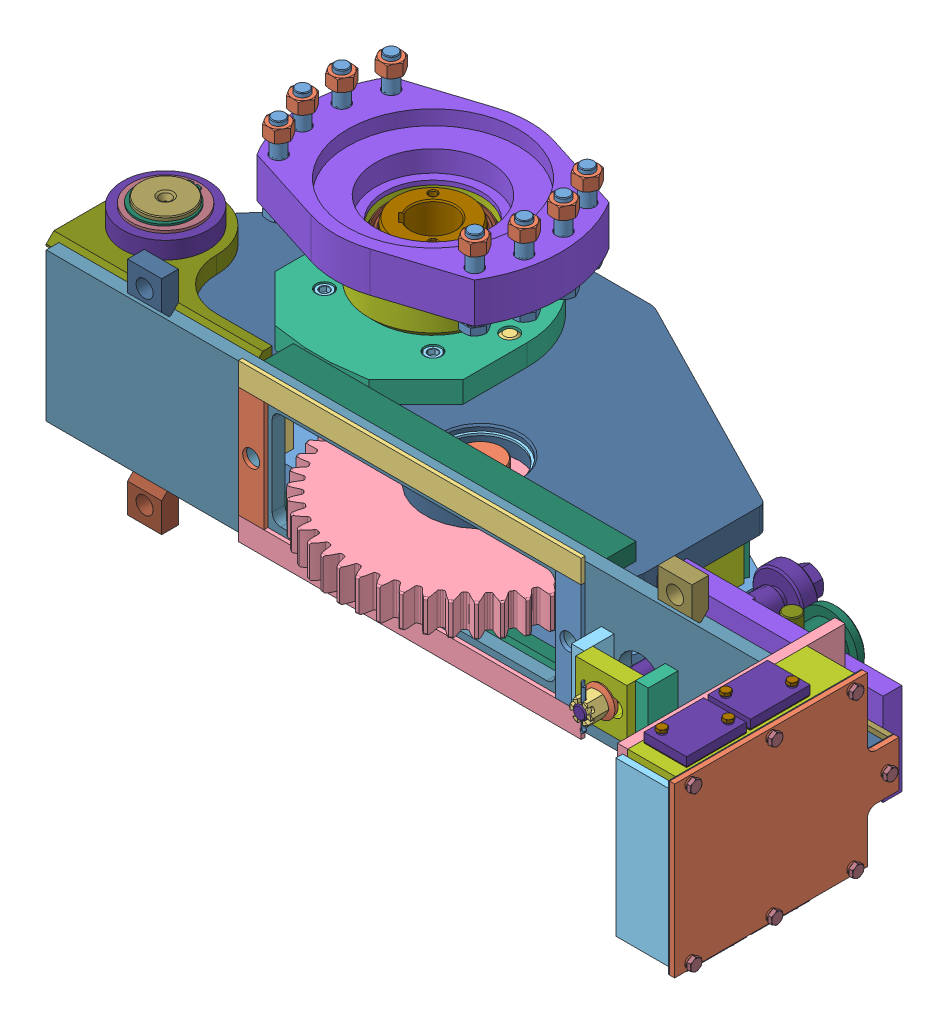
SolidWorks assembly g1_3_1_1, configuration 默认. Lengths in mm.
Overall size (957.4 359.9 530).
207 component instances, 96 part files, 0 mates.
Components (placement in the parent):
- g1_3_1_1_5_2-1: g1_3_1_1_5_2 [默认] at origin size (926 108 318.6)
  - g1_3_1_1_5-1_af1_2-1: g1_3_1_1_5-1_af1_2 [默认] at origin size (661 29 318.6)
  - g1_3_1_1_5-2_af0_2-1: g1_3_1_1_5-2_af0_2 [默认] at (-213.2 29 0) size (100 50 100)
  - g1_3_1_1_5-3_2-1: g1_3_1_1_5-3_2 [默认] at (-103.2 54 50) x (1 0 0) z (0 1 0) size (160 10 50)
  - g1_3_1_1_5-4_2-1: g1_3_1_1_5-4_2 [默认] at (-149.9151 54 -132.7301) x (0 1 0) z (-0.659692 0 0.751536) size (50 10 223)
  - g1_3_1_1_5-5_2-1: g1_3_1_1_5-5_2 [默认] at (20.5 54 -217) x (1 0 0) z (0 1 0) size (194 10 50)
  - g1_3_1_1_5-6_2-1: g1_3_1_1_5-6_2 [默认] at (248.4498 54 -161.5242) x (0 1 0) z (0.890083 0 0.455798) size (50 10 284)
  - g1_3_1_1_5-7_2-1: g1_3_1_1_5-7_2 [默认] at (377.8 54 -43.9) x (0 0 -1) z (0 1 0) size (87 10 50)
  - g1_3_1_1_5-9_af0_2-1: g1_3_1_1_5-9_af0_2 [默认] at (502.8 54 24.6) x (1 0 0) z (0 1 0) size (300 25 108)
  - g1_3_1_1_5-8_2-1: g1_3_1_1_5-8_2 [默认] at (437.8 54 49.6) x (1 0 0) z (0 1 0) size (60 50 60)
  - g1_3_1_1_5-1_af0_2-1: g1_3_1_1_5-1_af0_2 [默认] at (0 79 0) size (661 29 318.6)
  - g1_3_1_1_5_more_2-1: g1_3_1_1_5_more_2 [默认] at origin size (139.2 108 206.2)
- g1_3_1_1_4_2-1: g1_3_1_1_4_2 [默认] at (-213.2 -63.3 0) size (80 236.35 80)
  - g1_3_1_1_4-1_2-1: g1_3_1_1_4-1_2 [默认] at origin size (60 234 60.04)
  - g1_3_1_1_4-3_2-1: g1_3_1_1_4-3_2 [默认] at (0 6.7 0) size (80 3 80)
  - g1_3_1_1_4-3_2-2: g1_3_1_1_4-3_2 [默认] at (0 224.3 0) size (80 3 80)
  - g1_3_1_1_4-2_2-1: g1_3_1_1_4-2_2 [默认] at (0 174.3 0) size (72 50 72)
  - g1_3_1_1_4-2_2-2: g1_3_1_1_4-2_2 [默认] at (0 9.7 0) size (72 50 72)
  - g1_3_1_1_4-2_2-3: g1_3_1_1_4-2_2 [默认] at (0 62.7 0) size (72 50 72)
  - g1_3_1_1_4-2_2-4: g1_3_1_1_4-2_2 [默认] at (0 121.3 0) size (72 50 72)
  - 60_gb894_1_2-1: 60_gb894_1_2 [默认] at (1.95 4.5 -28.4332) x (-1 0 0) z (0 1 0) size (65.16 69.76 2)
  - 60_gb894_1_2-2: 60_gb894_1_2 [默认] at (1.95 227.5 -28.4332) x (-1 0 0) z (0 1 0) size (65.16 69.76 2)
  - 10_jb982_2-1: 10_jb982_2 [默认] at (0 -1 0) size (16 2.7 16)
- g1_3_1_1_2_2-1: g1_3_1_1_2_2 [默认] at (0 -30 -100.4) size (219.6 152 245)
  - g1_3_1_1_2-1_2-1: g1_3_1_1_2-1_2 [默认] at origin size (219.6 61 245)
  - g1_3_1_1_2-2_2-1: g1_3_1_1_2-2_2 [默认] at (0 152 0) x (-0.047609 0 0.998866) z (0 1 0) size (120.16 120.16 117)
  - g1_3_1_1_2-3_2-1: g1_3_1_1_2-3_2 [默认] at (-20.1525 129 20.1525) x (0 -1 0) z (0.707107 0 0.707107) size (28 11 14)
- g1_3_1_1_3_2-1: g1_3_1_1_3_2 [默认] at (172.8 54 16.6) x (0 -1 0) z (0 0 1) size (103.5 321.87 322.01)
  - g1_3_1_1_3-1_2-1: g1_3_1_1_3-1_2 [默认] at origin size (103.5 52 52)
  - 16x10x45_gb1096_2-1: 16x10x45_gb1096_2 [默认] at (-0.5 0 25) x (1 0 0) z (0 0 -1) size (45 16 10)
  - _X2_60F08F6E_X0_g1_3_1_1_3-2_2-1: _X2_60F08F6E_X0_g1_3_1_1_3-2_2 [默认] at (25 0 0) x (0 0 1) z (1 0 0) size (322.01 321.87 50.08)
  - 90_gb893_1_2-1: 90_gb893_1_2 [默认] at (45.05 0 -2.4333) x (0 1 0) z (1 0 0) size (93.5 89.63 2.5)
  - 90_gb893_1_2-2: 90_gb893_1_2 [默认] at (-47.55 0 -2.4333) x (0 1 0) z (1 0 0) size (93.5 89.63 2.5)
- g1_3_1_1_1_3-1: g1_3_1_1_1_3 [默认] at (0 83 -100.4) size (300 165.8 249)
  - g1_3_1_1_1_1_2-1: g1_3_1_1_1_1_2 [默认] at origin size (300 154 249)
    - g1_3_1_1_1_1-1_af0_2-1: g1_3_1_1_1_1-1_af0_2 [默认] at origin size (220 42 245)
    - g1_3_1_1_1_1-2_af0_2-1: g1_3_1_1_1_1-2_af0_2 [默认] at (0 50 0) size (150 65.01 150)
    - g1_3_1_1_1_1-3_af0_2-1: g1_3_1_1_1_1-3_af0_2 [默认] at (0 140 0) size (300 47 228)
  - g1_3_1_1_1-2_2-1: g1_3_1_1_1-2_2 [默认] at (0 122.2 0) x (0.707107 0 0.707107) z (0.707107 0 -0.707107) size (90 126 90)
  - g1_3_1_1_1-1_2-1: g1_3_1_1_1-1_2 [默认] at (0 77 0) x (0 1 0) z (0 0 1) size (20 110 110)
  - b90x110x12_gb9877_1_2-1: b90x110x12_gb9877_1_2 [默认] at (0 66.9 0) size (108.6 17.9 108.6)
    - b90x110x12_gb9877_1_rubber_2-1: b90x110x12_gb9877_1_rubber_2 [默认] at origin size (108.6 12 108.6)
    - b90x110x12_gb9877_1_frame_2-1: b90x110x12_gb9877_1_frame_2 [默认] at (0 -2.4 0) x (-1 0 0) z (0 0 1) size (107.2 9.5 107.2)
  - b90x110x12_gb9877_1_2-2: b90x110x12_gb9877_1_2 [默认] at (0 104.8 0) size (108.6 17.9 108.6)
    - b90x110x12_gb9877_1_rubber_2-1: b90x110x12_gb9877_1_rubber_2 [默认] at origin size (108.6 12 108.6)
    - b90x110x12_gb9877_1_frame_2-1: b90x110x12_gb9877_1_frame_2 [默认] at (0 -2.4 0) x (-1 0 0) z (0 0 1) size (107.2 9.5 107.2)
  - 80_gb894_1_2-1: 80_gb894_1_2 [默认] at (-2.4 11.1 -38.1746) x (1 0 0) z (0 -1 0) size (85.83 90.87 2.5)
- g1_3_1_1_6_2-1: g1_3_1_1_6_2 [默认] at (172.8 54 95) x (1 0 0) z (0 1 0) size (880 200 260)
  - g1_3_1_1_6-4_af0_2-1: g1_3_1_1_6-4_af0_2 [默认] at origin size (850 15 174)
  - g1_3_1_1_6-8_2-1: g1_3_1_1_6-8_2 [默认] at (0 40 57) x (1 0 0) z (0 -1 0) size (402 20 44.8)
  - g1_3_1_1_6-8_2-2: g1_3_1_1_6-8_2 [默认] at (0 40 -77) x (1 0 0) z (0 -1 0) size (402 20 44.8)
  - g1_3_1_1_6-1_2-1: g1_3_1_1_6-1_2 [默认] at (-386 95 -87) x (1 0 0) z (0 -1 0) size (245 20 140)
  - g1_3_1_1_6-1_2-2: g1_3_1_1_6-1_2 [默认] at (-386 95 67) x (1 0 0) z (0 -1 0) size (245 20 140)
  - g1_3_1_1_6-3_2-1: g1_3_1_1_6-3_2 [默认] at (-386 95 87) x (-1 0 0) z (0 1 0) size (100 20 100)
  - g1_3_1_1_6-3_2-2: g1_3_1_1_6-3_2 [默认] at (-386 95 -107) x (-1 0 0) z (0 1 0) size (100 20 100)
  - g1_3_1_1_6-2_2-1: g1_3_1_1_6-2_2 [默认] at (-386 95 57) x (-1 0 0) z (0 1 0) size (100 10 100)
  - g1_3_1_1_6-2_2-2: g1_3_1_1_6-2_2 [默认] at (-386 95 -57) x (1 0 0) z (0 1 0) size (100 10 100)
  - g1_3_1_1_6-6_af1_2-1: g1_3_1_1_6-6_af1_2 [默认] at (186 -5 0) x (0 0 -1) z (1 0 0) size (130 4.6 30)
  - g1_3_1_1_6-6_af0_2-1: g1_3_1_1_6-6_af0_2 [默认] at (-186 -5 0) x (0 0 -1) z (1 0 0) size (130 4.6 30)
  - g1_3_1_1_6-7_af0_2-1: g1_3_1_1_6-7_af0_2 [默认] at (0 0 78.5) x (1 0 0) z (0 0 -1) size (402 4.6 27)
  - g1_3_1_1_6-7_af1_2-1: g1_3_1_1_6-7_af1_2 [默认] at (0 -5 -78.5) size (402 4.6 27)
  - g1_3_1_1_6-9_2-1: g1_3_1_1_6-9_2 [默认] at (220 -17 0) x (0 1 0) z (0 0 -1) size (35 15 60)
  - g1_3_1_1_6-9_af0_2-1: g1_3_1_1_6-9_af0_2 [默认] at (310 -17 0) x (0 1 0) z (0 0 1) size (35 15 60)
  - g1_3_1_1_6-10_2-1: g1_3_1_1_6-10_2 [默认] at (265 -45 0) size (60 20 60)
  - g1_3_1_1_6-12_af0_2-1: g1_3_1_1_6-12_af0_2 [默认] at (434 25 0.5) x (0 0 1) z (0 -1 0) size (120 25 80)
  - g1_3_1_1_6-11_af0_2-1: g1_3_1_1_6-11_af0_2 [默认] at (357 15 0) size (94 40 60)
  - g1_3_1_1_6-5_af0_2-1: g1_3_1_1_6-5_af0_2 [默认] at (-311 -5 108.5) x (0 0 -1) z (1 0 0) size (43 19.6 40)
  - g1_3_1_1_6-5_af1_2-1: g1_3_1_1_6-5_af1_2 [默认] at (-311 -5 -108.5) x (0 0 1) z (-1 0 0) size (43 19.6 40)
  - g1_3_1_1_6-5_af2_2-1: g1_3_1_1_6-5_af2_2 [默认] at (311 -5 108.5) x (0 0 -1) z (1 0 0) size (43 19.6 40)
  - g1_3_1_1_6-5_af3_2-1: g1_3_1_1_6-5_af3_2 [默认] at (311 -5 -108.5) x (0 0 1) z (-1 0 0) size (43 19.6 40)
  - g1_3_1_1_6_more_2-1: g1_3_1_1_6_more_2 [默认] at origin size (109 70.2 96)
- g1_3_1_1-1_2-1: g1_3_1_1-1_2 [默认] at (512.8 54 49.5) x (1 0 0) z (0 1 0) size (70 135 70)
- g1_3_1_1-2_2-1: g1_3_1_1-2_2 [默认] at (512.8 43 -8.5) x (0 1 0) z (0 0 1) size (130 25 25)
- g1_3_1_1_7_2-1: g1_3_1_1_7_2 [默认] at (437.8 54 78.9833) x (0 0 1) z (0 1 0) size (272.02 63.51 60)
  - g1_3_1_1_7-1_2-1: g1_3_1_1_7-1_2 [默认] at origin size (272.02 60 60)
  - g1_3_1_1_7-2_2-1: g1_3_1_1_7-2_2 [默认] at (-104.3833 -31.7543 0) x (0 1 0) z (1 0 0) size (63.51 55 25)
  - 4x40_gb91_2-1: 4x40_gb91_2 [默认] at (82.0173 -2 29.7543) x (0 0 1) z (-1 -0.000312 0) size (52 6.04 4)
  - a35_5_gb1972_2-1: a35_5_gb1972_2 [默认] at (39.2167 0 0) x (0 0.075145 0.997173) z (0 0.997173 -0.075145) size (35.5 7.2 35.5)
  - a35_5_gb1972_2-2: a35_5_gb1972_2 [默认] at (62.8167 0 0) x (0 -0.99777 0.066751) z (0 -0.066751 -0.99777) size (35.5 7.2 35.5)
  - m16a_gb6178_2-1: m16a_gb6178_2 [默认] at (85.8167 13.8564 0) x (0 -1 0) z (-1 0 0) size (27.71 24 20.8)
- g1_3_1_1_8_2-1: g1_3_1_1_8_2 [默认] at (601.8 66.5 157.5) x (0 -1 0) z (0 0 1) size (230.2 85.4 268.3)
  - g1_3_1_1_8_1_af0_2-1: g1_3_1_1_8_1_af0_2 [默认] at origin size (197 68 263)
    - g1_3_1_1_8_1-3_af1_2-1: g1_3_1_1_8_1-3_af1_2 [默认] at origin size (197 12 255)
    - g1_3_1_1_8_1-1_2-1: g1_3_1_1_8_1-1_2 [默认] at (0 37 127.5) x (1 0 0) z (0 -1 0) size (181 8 62)
    - g1_3_1_1_8_1-2_af1_2-1: g1_3_1_1_8_1-2_af1_2 [默认] at (98.5 40 22.5) x (0 1 0) z (0 0 1) size (56 16 210)
    - g1_3_1_1_8_1-2_af0_2-1: g1_3_1_1_8_1-2_af0_2 [默认] at (-98.5 40 22.5) x (0 1 0) z (0 0 -1) size (56 16 210)
    - g1_3_1_1_8_1-5_2-1: g1_3_1_1_8_1-5_2 [默认] at (0 40 -82.5) x (1 0 0) z (0 1 0) size (165 8 56)
    - g1_3_1_1_8_1-7_af0_2-1: g1_3_1_1_8_1-7_af0_2 [默认] at (12.5 57 -106) size (30 6 31)
    - g1_3_1_1_8_1-6_2-1: g1_3_1_1_8_1-6_2 [默认] at (27.5 40 -106) x (0 1 0) z (0 0 -1) size (56 6 31)
    - g1_3_1_1_8_1-6_2-2: g1_3_1_1_8_1-6_2 [默认] at (-8.5 40 -106) x (0 1 0) z (0 0 -1) size (56 6 31)
    - g1_3_1_1_8_1-4_af1_2-1: g1_3_1_1_8_1-4_af1_2 [默认] at (-10 12 5) size (105 17 85)
    - g1_3_1_1_8_1-8_af0_2-1: g1_3_1_1_8_1-8_af0_2 [默认] at (12.5 40 -127.5) x (0 1 0) z (1 0 0) size (56 6 54)
    - g1_3_1_1_8_1_af0_more_2-1: g1_3_1_1_8_1_af0_more_2 [默认] at origin size (197 61 238)
  - g1_3_1_1_8-3_2-1: g1_3_1_1_8-3_2 [默认] at (12.5 37 -32.7987) x (0 0 -1) z (0 1 0) size (229 15 15)
  - g1_3_1_1_8-6_2-1: g1_3_1_1_8-6_2 [默认] at (12.5 37 30.1) x (-1 0 0) z (0 1 0) size (26 60 26)
  - g1_3_1_1_8-5_2-1: g1_3_1_1_8-5_2 [默认] at (12.5 29 -27.5) size (60 24 20)
  - g1_3_1_1_8-1_2-1: g1_3_1_1_8-1_2 [默认] at (109.5 39.7 76.2) x (0 0 -1) z (0 1 0) size (70 10 50)
  - g1_3_1_1_8-1_2-2: g1_3_1_1_8-1_2 [默认] at (109.5 39.7 1.2) x (0 0 -1) z (0 1 0) size (70 10 50)
  - g1_3_1_1_8-1_2-3: g1_3_1_1_8-1_2 [默认] at (-99.5 40.3 76.8) x (0 0 1) z (0 -1 0) size (70 10 50)
  - g1_3_1_1_8-1_2-4: g1_3_1_1_8-1_2 [默认] at (-99.5 39.7 1.2) x (0 0 -1) z (0 1 0) size (70 10 50)
  - g1_3_1_1_8-2_2-1: g1_3_1_1_8-2_2 [默认] at (99.5 39.7 76.8) x (0 1 0) z (0 0 1) size (50 1 70)
  - g1_3_1_1_8-2_2-2: g1_3_1_1_8-2_2 [默认] at (99.5 39.7 1.8) x (0 1 0) z (0 0 1) size (50 1 70)
  - g1_3_1_1_8-2_2-3: g1_3_1_1_8-2_2 [默认] at (-98.5 40.3 76.8) x (0 1 0) z (0 0 1) size (50 1 70)
  - g1_3_1_1_8-2_2-4: g1_3_1_1_8-2_2 [默认] at (-98.5 39.7 1.8) x (0 1 0) z (0 0 1) size (50 1 70)
  - g1_3_1_1_8-8_2-1: g1_3_1_1_8-8_2 [默认] at (0 68 22.5) x (0 0 -1) z (1 0 0) size (263 1 197)
  - g1_3_1_1_8-7_2-1: g1_3_1_1_8-7_2 [默认] at (0 69 22.5) x (0 0 -1) z (1 0 0) size (263 6 197)
  - g1_3_1_1_8-9_af0_2-1: g1_3_1_1_8-9_af0_2 [默认] at (-42.5 17 5.5) size (34 10 74)
  - g1_3_1_1_8-10_2-1: g1_3_1_1_8-10_2 [默认] at (12.5 37 -127.5) x (1 0 0) z (0 1 0) size (40 2 32)
  - g1_3_1_1_8-4_2-1: g1_3_1_1_8-4_2 [默认] at (12.5 37 -69.8) x (1 0 0) z (0 1 0) size (22 3 22)
  - ya2x20x90-2_gb2089_af0_2-1: ya2x20x90-2_gb2089_af0_2 [默认] at (12.5 37 -82.5) x (0 0 -1) z (1 0 0) size (92.3 24.62 24.71)
  - 14x2_65_gb3452_1_2-1: 14x2_65_gb3452_1_2 [默认] at (12.5 37 -124.5) x (0 0 1) z (0 1 0) size (2.65 19.38 19.38)
  - 6_gb93_2-1: 6_gb93_2 [默认] at (111.1 54.3 -23.2) x (0 -1 0) z (-1 0 0) size (9.3 9.3 1.6)
  - m6x20_gb5783_2-1: m6x20_gb5783_2 [默认] at (111.1 54.3 -23.2) x (0 -1 0) z (0 0 1) size (11.55 24 10)
  - 6_gb93_2-2: 6_gb93_2 [默认] at (111.1 25.7 26.2) x (0 -1 0) z (-1 0 0) size (9.3 9.3 1.6)
  - m6x20_gb5783_2-2: m6x20_gb5783_2 [默认] at (111.1 25.7 26.2) x (0 -1 0) z (0 0 1) size (11.55 24 10)
  - 6_gb93_2-3: 6_gb93_2 [默认] at (111.1 54.3 51.8) x (0 -1 0) z (-1 0 0) size (9.3 9.3 1.6)
  - m6x20_gb5783_2-3: m6x20_gb5783_2 [默认] at (111.1 54.3 51.8) x (0 -1 0) z (0 0 1) size (11.55 24 10)
  - 6_gb93_2-4: 6_gb93_2 [默认] at (111.1 25.7 101.2) x (0 -1 0) z (-1 0 0) size (9.3 9.3 1.6)
  - m6x20_gb5783_2-4: m6x20_gb5783_2 [默认] at (111.1 25.7 101.2) x (0 -1 0) z (0 0 1) size (11.55 24 10)
  - 6_gb93_2-5: 6_gb93_2 [默认] at (-111.1 54.3 -23.2) x (0 1 0) z (1 0 0) size (9.3 9.3 1.6)
  - m6x20_gb5783_2-5: m6x20_gb5783_2 [默认] at (-111.1 54.3 -23.2) x (0 1 0) z (0 0 1) size (11.55 24 10)
  - 6_gb93_2-6: 6_gb93_2 [默认] at (-111.1 25.7 26.2) x (0 1 0) z (1 0 0) size (9.3 9.3 1.6)
  - m6x20_gb5783_2-6: m6x20_gb5783_2 [默认] at (-111.1 25.7 26.2) x (0 1 0) z (0 0 1) size (11.55 24 10)
  - 6_gb93_2-7: 6_gb93_2 [默认] at (-111.1 54.3 51.8) x (0 1 0) z (1 0 0) size (9.3 9.3 1.6)
  - m6x20_gb5783_2-7: m6x20_gb5783_2 [默认] at (-111.1 54.3 51.8) x (0 1 0) z (0 0 1) size (11.55 24 10)
  - 6_gb93_2-8: 6_gb93_2 [默认] at (-111.1 25.7 101.2) x (0 1 0) z (1 0 0) size (9.3 9.3 1.6)
  - m6x20_gb5783_2-8: m6x20_gb5783_2 [默认] at (-111.1 25.7 101.2) x (0 1 0) z (0 0 1) size (11.55 24 10)
  - 15_gb894_1_2-1: 15_gb894_1_2 [默认] at (12 29.8675 -73.9) size (17.18 18.67 1.11)
  - 15_gb894_1_2-2: 15_gb894_1_2 [默认] at (12 29.8675 29) size (17.18 18.67 1.11)
  - 15_gb894_1_2-3: 15_gb894_1_2 [默认] at (12 29.8675 134.5) size (17.18 18.67 1.11)
  - 8_gb93_2-1: 8_gb93_2 [默认] at (32.5 53 -27.5) x (-1 0 0) z (0 1 0) size (12.3 12.3 2.1)
  - m8x40_gb5782_2-1: m8x40_gb5782_2 [默认] at (32.5 55.1 -27.5) size (15.01 45.3 13)
  - 8_gb93_2-2: 8_gb93_2 [默认] at (-7.5 53 -27.5) x (-1 0 0) z (0 1 0) size (12.3 12.3 2.1)
  - m8x40_gb5782_2-2: m8x40_gb5782_2 [默认] at (-7.5 55.1 -27.5) size (15.01 45.3 13)
  - 8_gb93_2-3: 8_gb93_2 [默认] at (90.5 75 -72.5) x (-1 0 0) z (0 1 0) size (12.3 12.3 2.1)
  - m8x20_gb5783_dakexiu_2-1: m8x20_gb5783_dakexiu_2 [默认] at (90.5 77.1 -72.5) size (15.01 25.3 13)
  - 8_gb93_2-4: 8_gb93_2 [默认] at (90.5 75 22.5) x (-1 0 0) z (0 1 0) size (12.3 12.3 2.1)
  - m8x20_gb5783_dakexiu_2-2: m8x20_gb5783_dakexiu_2 [默认] at (90.5 77.1 22.5) size (15.01 25.3 13)
  - 8_gb93_2-5: 8_gb93_2 [默认] at (90.5 75 117.5) x (-1 0 0) z (0 1 0) size (12.3 12.3 2.1)
  - m8x20_gb5783_dakexiu_2-3: m8x20_gb5783_dakexiu_2 [默认] at (90.5 77.1 117.5) size (15.01 25.3 13)
  - 8_gb93_2-6: 8_gb93_2 [默认] at (-90.5 75 117.5) x (-1 0 0) z (0 1 0) size (12.3 12.3 2.1)
  - m8x20_gb5783_dakexiu_2-4: m8x20_gb5783_dakexiu_2 [默认] at (-90.5 77.1 117.5) size (15.01 25.3 13)
  - 8_gb93_2-7: 8_gb93_2 [默认] at (-90.5 75 22.5) x (-1 0 0) z (0 1 0) size (12.3 12.3 2.1)
  - m8x20_gb5783_dakexiu_2-5: m8x20_gb5783_dakexiu_2 [默认] at (-90.5 77.1 22.5) size (15.01 25.3 13)
  - 8_gb93_2-8: 8_gb93_2 [默认] at (-90.5 75 -72.5) x (-1 0 0) z (0 1 0) size (12.3 12.3 2.1)
  - m8x20_gb5783_dakexiu_2-6: m8x20_gb5783_dakexiu_2 [默认] at (-90.5 77.1 -72.5) size (15.01 25.3 13)
  - 8_gb93_2-9: 8_gb93_2 [默认] at (12.5 75 -112.5) x (-1 0 0) z (0 1 0) size (12.3 12.3 2.1)
  - m8x20_gb5783_dakexiu_2-7: m8x20_gb5783_dakexiu_2 [默认] at (12.5 77.1 -112.5) size (15.01 25.3 13)
  - m3x10_gb818_2-1: m3x10_gb818_2 [默认] at (57.5 2 60.5) size (5.81 12.5 5.77)
  - m3x10_gb818_2-2: m3x10_gb818_2 [默认] at (57.5 2 100.5) size (5.81 12.5 5.77)
  - m3x10_gb818_2-3: m3x10_gb818_2 [默认] at (-17.5 2 100.5) size (5.81 12.5 5.77)
  - m3x10_gb818_2-4: m3x10_gb818_2 [默认] at (-57.5 2 100.5) size (5.81 12.5 5.77)
  - m3x30_gb818_2-1: m3x30_gb818_2 [默认] at (-40.5 -3 7.5) size (5.81 32.5 5.77)
  - m3x30_gb818_2-2: m3x30_gb818_2 [默认] at (-40.5 -3 32.9) size (5.81 32.5 5.77)
  - 6_gb93_2-9: 6_gb93_2 [默认] at (-52.5 28.6 -17.5) x (1 0 0) z (0 -1 0) size (9.3 9.3 1.6)
  - m6x20_gb5783_2-9: m6x20_gb5783_2 [默认] at (-52.5 28.6 -17.5) size (11.55 24 10)
  - 6_gb93_2-10: 6_gb93_2 [默认] at (-32.5 28.6 -17.5) x (1 0 0) z (0 -1 0) size (9.3 9.3 1.6)
  - m6x20_gb5783_2-10: m6x20_gb5783_2 [默认] at (-32.5 28.6 -17.5) size (11.55 24 10)
  - 5x14_gb119_2_2-1: 5x14_gb119_2_2 [默认] at (-42.5 27 -3.5) size (5 14 5)
  - m3x6_gb818_2-1: m3x6_gb818_2 [默认] at (27.5 37 -123.5) x (1 0 0) z (0 1 0) size (5.81 8.5 5.77)
  - m3x6_gb818_2-2: m3x6_gb818_2 [默认] at (-2.5 37 -123.5) x (1 0 0) z (0 1 0) size (5.81 8.5 5.77)
- _X2_57AB5708_X0_16_gb93_2-1: _X2_57AB5708_X0_16_gb93_2 [默认] at (115 193.9 -166.4) x (-1 0 0) z (0 1 0) size (24.4 24.4 4.1)
- m16x90_gb5782_10_2-1: m16x90_gb5782_10_2 [默认] at (115 193.9 -166.4) x (-1 0 0) z (0 0 1) size (27.71 100 24)
- m16_gb6170_10_2-1: m16_gb6170_10_2 [默认] at (101.1436 278.9 -166.4) x (1 0 0) z (0 -1 0) size (27.71 24 14.8)
- _X2_57AB5708_X0_16_gb93_2-2: _X2_57AB5708_X0_16_gb93_2 [默认] at (130 193.9 -123.4) x (-1 0 0) z (0 1 0) size (24.4 24.4 4.1)
- m16x90_gb5782_10_2-2: m16x90_gb5782_10_2 [默认] at (130 193.9 -123.4) x (-1 0 0) z (0 0 1) size (27.71 100 24)
- m16_gb6170_10_2-2: m16_gb6170_10_2 [默认] at (116.1436 278.9 -123.4) x (1 0 0) z (0 -1 0) size (27.71 24 14.8)
- _X2_57AB5708_X0_16_gb93_2-3: _X2_57AB5708_X0_16_gb93_2 [默认] at (130 193.9 -77.4) x (-1 0 0) z (0 1 0) size (24.4 24.4 4.1)
- m16x90_gb5782_10_2-3: m16x90_gb5782_10_2 [默认] at (130 193.9 -77.4) x (-1 0 0) z (0 0 1) size (27.71 100 24)
- m16_gb6170_10_2-3: m16_gb6170_10_2 [默认] at (116.1436 278.9 -77.4) x (1 0 0) z (0 -1 0) size (27.71 24 14.8)
- _X2_57AB5708_X0_16_gb93_2-4: _X2_57AB5708_X0_16_gb93_2 [默认] at (115 193.9 -34.4) x (-1 0 0) z (0 1 0) size (24.4 24.4 4.1)
- m16x90_gb5782_10_2-4: m16x90_gb5782_10_2 [默认] at (115 193.9 -34.4) x (-1 0 0) z (0 0 1) size (27.71 100 24)
- m16_gb6170_10_2-4: m16_gb6170_10_2 [默认] at (101.1436 278.9 -34.4) x (1 0 0) z (0 -1 0) size (27.71 24 14.8)
- _X2_57AB5708_X0_16_gb93_2-5: _X2_57AB5708_X0_16_gb93_2 [默认] at (-115 193.9 -166.4) x (-1 0 0) z (0 1 0) size (24.4 24.4 4.1)
- m16x90_gb5782_10_2-5: m16x90_gb5782_10_2 [默认] at (-115 193.9 -166.4) x (-1 0 0) z (0 0 1) size (27.71 100 24)
- m16_gb6170_10_2-5: m16_gb6170_10_2 [默认] at (-128.8564 278.9 -166.4) x (1 0 0) z (0 -1 0) size (27.71 24 14.8)
- _X2_57AB5708_X0_16_gb93_2-6: _X2_57AB5708_X0_16_gb93_2 [默认] at (-130 193.9 -123.4) x (-1 0 0) z (0 1 0) size (24.4 24.4 4.1)
- m16x90_gb5782_10_2-6: m16x90_gb5782_10_2 [默认] at (-130 193.9 -123.4) x (-1 0 0) z (0 0 1) size (27.71 100 24)
- m16_gb6170_10_2-6: m16_gb6170_10_2 [默认] at (-143.8564 278.9 -123.4) x (1 0 0) z (0 -1 0) size (27.71 24 14.8)
- _X2_57AB5708_X0_16_gb93_2-7: _X2_57AB5708_X0_16_gb93_2 [默认] at (-130 193.9 -77.4) x (-1 0 0) z (0 1 0) size (24.4 24.4 4.1)
- m16x90_gb5782_10_2-7: m16x90_gb5782_10_2 [默认] at (-130 193.9 -77.4) x (-1 0 0) z (0 0 1) size (27.71 100 24)
- m16_gb6170_10_2-7: m16_gb6170_10_2 [默认] at (-143.8564 278.9 -77.4) x (1 0 0) z (0 -1 0) size (27.71 24 14.8)
- _X2_57AB5708_X0_16_gb93_2-8: _X2_57AB5708_X0_16_gb93_2 [默认] at (-115 193.9 -34.4) x (-1 0 0) z (0 1 0) size (24.4 24.4 4.1)
- m16x90_gb5782_10_2-8: m16x90_gb5782_10_2 [默认] at (-115 193.9 -34.4) x (-1 0 0) z (0 0 1) size (27.71 100 24)
- m16_gb6170_10_2-8: m16_gb6170_10_2 [默认] at (-128.8564 278.9 -34.4) x (1 0 0) z (0 -1 0) size (27.71 24 14.8)
- 20x40_gb119_2_2-1: 20x40_gb119_2_2 [默认] at (90 133 -100.4) size (20 40 20)
- 20x40_gb119_2_2-2: 20x40_gb119_2_2 [默认] at (90 10 -100.4) size (20 40 20)
- _X2_57AB5708_X0_12_gb93_2-1: _X2_57AB5708_X0_12_gb93_2 [默认] at (63.6 -14 -36.8) x (1 0 0) z (0 -1 0) size (18.4 18.4 3.1)
- m12x35_gb70_1_2-1: m12x35_gb70_1_2 [默认] at (63.6 -29.1 -36.8) x (-1 0 0) z (0 0 1) size (18 47.51 18)
- _X2_57AB5708_X0_12_gb93_2-2: _X2_57AB5708_X0_12_gb93_2 [默认] at (-63.6 -14 -36.8) x (1 0 0) z (0 -1 0) size (18.4 18.4 3.1)
- m12x35_gb70_1_2-2: m12x35_gb70_1_2 [默认] at (-63.6 -29.1 -36.8) x (-1 0 0) z (0 0 1) size (18 47.51 18)
- _X2_57AB5708_X0_12_gb93_2-3: _X2_57AB5708_X0_12_gb93_2 [默认] at (-63.6 -14 -164) x (1 0 0) z (0 -1 0) size (18.4 18.4 3.1)
- m12x35_gb70_1_2-3: m12x35_gb70_1_2 [默认] at (-63.6 -29.1 -164) x (-1 0 0) z (0 0 1) size (18 47.51 18)
- _X2_57AB5708_X0_12_gb93_2-4: _X2_57AB5708_X0_12_gb93_2 [默认] at (63.6 -14 -164) x (1 0 0) z (0 -1 0) size (18.4 18.4 3.1)
- m12x35_gb70_1_2-4: m12x35_gb70_1_2 [默认] at (63.6 -29.1 -164) x (-1 0 0) z (0 0 1) size (18 47.51 18)
- _X2_57AB5708_X0_12_gb93_2-5: _X2_57AB5708_X0_12_gb93_2 [默认] at (63.6 117 -164) x (-1 0 0) z (0 1 0) size (18.4 18.4 3.1)
- m12x35_gb70_1_2-5: m12x35_gb70_1_2 [默认] at (63.6 132.1 -164) size (18 47.51 18)
- _X2_57AB5708_X0_12_gb93_2-6: _X2_57AB5708_X0_12_gb93_2 [默认] at (-63.6 117 -164) x (-1 0 0) z (0 1 0) size (18.4 18.4 3.1)
- m12x35_gb70_1_2-6: m12x35_gb70_1_2 [默认] at (-63.6 132.1 -164) size (18 47.51 18)
- _X2_57AB5708_X0_12_gb93_2-7: _X2_57AB5708_X0_12_gb93_2 [默认] at (-63.6 117 -36.8) x (-1 0 0) z (0 1 0) size (18.4 18.4 3.1)
- m12x35_gb70_1_2-7: m12x35_gb70_1_2 [默认] at (-63.6 132.1 -36.8) size (18 47.51 18)
- _X2_57AB5708_X0_12_gb93_2-8: _X2_57AB5708_X0_12_gb93_2 [默认] at (63.6 117 -36.8) x (-1 0 0) z (0 1 0) size (18.4 18.4 3.1)
- m12x35_gb70_1_2-8: m12x35_gb70_1_2 [默认] at (63.6 132.1 -36.8) size (18 47.51 18)
- _X2_57AB5708_X0_16_gb93_2-9: _X2_57AB5708_X0_16_gb93_2 [默认] at (613.8 14 45) x (0 1 0) z (1 0 0) size (24.4 24.4 4.1)
- _X2_87BA6813_X0_m16x35_gb5783_10_2-1: _X2_87BA6813_X0_m16x35_gb5783_10_2 [默认] at (617.9 14 45) x (0 -1 0) z (0 0 1) size (27.71 45 24)
- _X2_57AB5708_X0_16_gb93_2-10: _X2_57AB5708_X0_16_gb93_2 [默认] at (613.8 94 45) x (0 1 0) z (1 0 0) size (24.4 24.4 4.1)
- _X2_87BA6813_X0_m16x35_gb5783_10_2-2: _X2_87BA6813_X0_m16x35_gb5783_10_2 [默认] at (617.9 94 45) x (0 -1 0) z (0 0 1) size (27.71 45 24)
